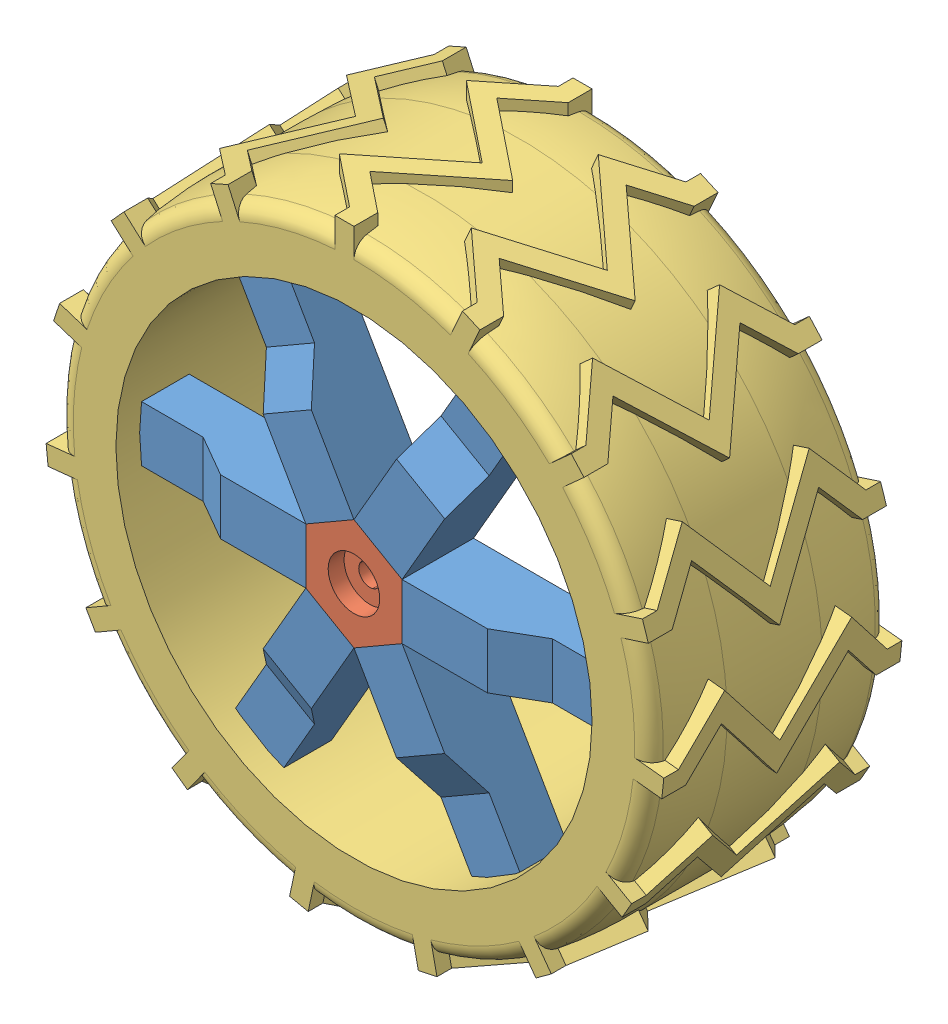
SolidWorks assembly wheel_assem, configuration Default. Lengths in mm.
Overall size (397.67 396.05 151.27).
8 component instances, 3 part files, 21 mates.
Components (placement in the parent):
- wheel_spoke-1: wheel_spoke [Default] at (-38.1992 -7.4775 -95.0997) x (0.866025 0.5 0) z (0 0 1) size (35 119.69 45)
- wheel_hub-1: wheel_hub [Default] at (-38.1988 -7.4782 -95.0997) x (0.866025 0.5 0) z (0 0 1) size (70 60.62 45)
- wheel_tire-1: wheel_tire [Default] at (-38.1988 182.5218 -147.5997) x (0 0 -1) z (1 0 0) size (151.27 396.05 397.67)
- wheel_spoke-2: wheel_spoke [Default] at (-38.1997 -7.4782 -95.0997) x (0 1 0) z (0 0 1) size (35 119.69 45)
- wheel_spoke-4: wheel_spoke [Default] at (-38.1992 -7.479 -95.0997) x (-0.866025 0.5 0) z (0 0 1) size (35 119.69 45)
- wheel_spoke-6: wheel_spoke [Default] at (-38.1983 -7.479 -95.0997) x (-0.866025 -0.5 0) z (0 0 1) size (35 119.69 45)
- wheel_spoke-8: wheel_spoke [Default] at (-38.1979 -7.4782 -95.0997) x (0 -1 0) z (0 0 1) size (35 119.69 45)
- wheel_spoke-10: wheel_spoke [Default] at (-38.1983 -7.4775 -95.0997) x (0.866025 -0.5 0) z (0 0 1) size (35 119.69 45)
Mates (geometry in assembly coordinates):
- Concentric1: concentric anti-aligned: cylinder of wheel_hub-1 through (-38.1988 -7.4782 -62.8007) axis (0 0 -1) radius 7; cylinder of wheel_tire-1 through (-38.1988 -7.4782 12.429) axis (0 0 1) radius 150
- Coincident1: coincident anti-aligned: plane of wheel_spoke-1 through (-73.1358 -5.3803 -72.5997) normal (0.834497 -0.551012 0); plane of wheel_hub-1 through (-73.1358 -5.3803 -72.5997) normal (-0.834497 0.551012 0)
- Coincident2: coincident aligned: plane of wheel_spoke-1 through (-38.1995 -7.4777 -72.5997) normal (0 0 1); plane of wheel_hub-1 through (-38.1988 -7.4782 -72.5997) normal (0 0 1)
- Coincident3: coincident aligned: line of wheel_spoke-1 through (-73.1358 -5.3803 -72.5997) axis (0 0 -1); line of wheel_hub-1 through (-73.1358 -5.3803 -72.5997) axis (0 0 -1)
- Coincident4: coincident anti-aligned: plane of wheel_hub-1 through (-57.4842 -36.6856 -72.5997) normal (-0.894439 -0.44719 0); plane of wheel_spoke-2 through (-57.4842 -36.6856 -72.5997) normal (0.894439 0.44719 0)
- Coincident5: coincident aligned: line of wheel_hub-1 through (-57.4842 -36.6856 -72.5997) axis (0 0 -1); line of wheel_spoke-2 through (-57.4842 -36.6856 -72.5997) axis (0 0 -1)
- Coincident6: coincident aligned: plane of wheel_hub-1 through (-38.1988 -7.4782 -72.5997) normal (0 0 1); plane of wheel_spoke-2 through (-38.1996 -7.4786 -72.5997) normal (0 0 1)
- Coincident7: coincident anti-aligned: plane of wheel_hub-1 through (-22.5471 -38.7836 -72.5997) normal (-0.059942 -0.998202 0); plane of wheel_spoke-4 through (-22.5471 -38.7836 -72.5997) normal (0.059942 0.998202 0)
- Coincident8: coincident aligned: plane of wheel_hub-1 through (-38.1988 -7.4782 -72.5997) normal (0 0 1); plane of wheel_spoke-4 through (-38.1988 -7.4791 -72.5997) normal (0 0 1)
- Coincident9: coincident aligned: line of wheel_hub-1 through (-22.5471 -38.7836 -72.5997) axis (0 0 -1); line of wheel_spoke-4 through (-22.5471 -38.7836 -72.5997) axis (0 0 -1)
- Coincident10: coincident anti-aligned: plane of wheel_hub-1 through (-3.2617 -9.5762 -72.5997) normal (0.834497 -0.551012 0); plane of wheel_spoke-6 through (-3.2617 -9.5762 -72.5997) normal (-0.834497 0.551012 0)
- Coincident11: coincident aligned: plane of wheel_hub-1 through (-38.1988 -7.4782 -72.5997) normal (0 0 1); plane of wheel_spoke-6 through (-38.198 -7.4787 -72.5997) normal (0 0 1)
- Coincident13: coincident aligned: line of wheel_hub-1 through (-3.2617 -9.5762 -72.5997) axis (0 0 -1); line of wheel_spoke-6 through (-3.2617 -9.5762 -72.5997) axis (0 0 -1)
- Coincident14: coincident anti-aligned: plane of wheel_hub-1 through (-18.9133 21.7292 -72.5997) normal (0.894439 0.44719 0); plane of wheel_spoke-8 through (-72.3347 21.7292 18.4096) normal (-0.894439 -0.44719 0)
- Coincident17: coincident aligned: plane of wheel_hub-1 through (-38.1988 -7.4782 -72.5997) normal (0 0 1); plane of wheel_spoke-8 through (-91.6194 -7.4778 18.4096) normal (0 0 1)
- Coincident18: coincident aligned: line of wheel_hub-1 through (-18.9133 21.7292 -72.5997) axis (0 0 -1); line of wheel_spoke-8 through (-72.3347 21.7292 18.4096) axis (0 0 -1)
- Coincident19: coincident anti-aligned: plane of wheel_hub-1 through (-53.8504 23.8271 -72.5997) normal (0.059942 0.998202 0); plane of wheel_spoke-10 through (-53.8504 23.8271 -72.5997) normal (-0.059942 -0.998202 0)
- Coincident20: coincident aligned: plane of wheel_hub-1 through (-38.1988 -7.4782 -72.5997) normal (0 0 1); plane of wheel_spoke-10 through (-38.1987 -7.4773 -72.5997) normal (0 0 1)
- Coincident21: coincident aligned: line of wheel_spoke-1 through (-53.8504 23.8271 -72.5997) axis (0 0 -1); line of wheel_spoke-10 through (-53.8504 23.8271 -72.5997) axis (0 0 -1)
- Coincident22: coincident aligned: plane of wheel_tire-1 through (-38.1988 142.5218 -72.5997) normal (0 0 1); plane of wheel_spoke-10 through (-38.1987 -7.4773 -72.5997) normal (0 0 1)
- Parallel1: parallel anti-aligned: plane of wheel_spoke-8 through (110.7778 -24.9782 -72.5997) normal (0 -1 0)
